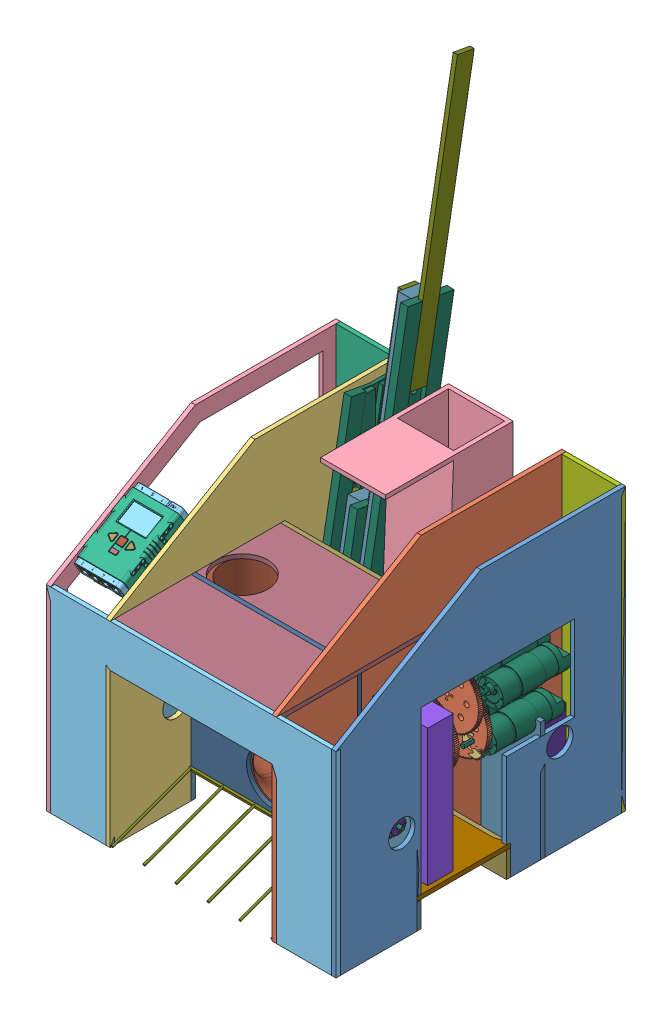
SolidWorks assembly 4290, configuration Default. Lengths in mm.
Overall size (457.2 989.75 483.92).
153 component instances, 53 part files, 145 mates.
Components (placement in the parent):
- Frame Exterior Left Outer-3: Frame Exterior Left Outer [Default] at (209.55 0 215.9) x (0 0 -1) z (1 0 0) size (431.8 419.1 6.35)
- Frame Exterior Left Inner-1: Frame Exterior Left Inner [Default] at (120.65 0 215.9) x (0 0 -1) z (1 0 0) size (431.8 419.1 6.35)
- Frame Exterior Right Inner-1: Frame Exterior Right Inner [Default] at (-127 0 215.9) x (0 0 -1) z (1 0 0) size (431.8 419.1 6.35)
- Frame Exterior Right Outer-1: Frame Exterior Right Outer [Default] at (-215.9 0 215.9) x (0 0 -1) z (1 0 0) size (431.8 419.1 6.35)
- Frame Exterior Front-1: Frame Exterior Front [Default] at (-215.9 0 209.55) size (431.8 292.1 6.35)
- Frame Exterior Back Right-1: Frame Exterior Back Right [Default] at (-215.9 0 -215.9) size (95.25 419.1 6.35)
- Frame Exterior Back Left-1: Frame Exterior Back Left [Default] at (120.65 0 -215.9) size (95.25 419.1 6.35)
- Blower Mockup-1: Blower Mockup [Default] at (209.55 57.15 34.8025) size (190.5 203.2 38.1)
- Frame Bottom Center-1: Frame Bottom Center [Default] at (-215.9 50.8 95.25) x (1 0 0) z (0 1 0) size (431.8 139.7 6.35)
- Frame Intake Front-1: Frame Intake Front [Default] at (-127 50.8 88.9) size (254 254 6.35)
- Ball Intake Tube-1: Ball Intake Tube [Default] at (-120.65 57.15 12.7) size (165.1 241.3 76.2)
- Frame Interior Intake Back-1: Frame Interior Intake Back [Default] at (-215.9 12.7 -44.45) size (431.8 292.1 6.35)
- Frame Interior Intake Top-1: Frame Interior Intake Top [Default] at (-127 298.45 215.9) x (1 0 0) z (0 1 0) size (254 254 6.35)
- Lift Spacer-1: Lift Spacer [Default] at (-109.5375 296.7142 -164.6027) x (1 0 0) z (0 -0.174694 -0.984623) size (19.05 444.5 38.1)
- Lift Spacer-2: Lift Spacer [Default] at (-79.375 550.9074 -209.7022) x (1 0 0) z (0 -0.174694 -0.984623) size (19.05 444.5 38.1)
- Lift Slide A-1: Lift Slide A [Default] at (-115.9125 211.5413 -131.54) x (0 0.984623 -0.174694) z (0 -0.174694 -0.984623) size (406.4 11.11 69.85)
- Lift Slide B-1: Lift Slide B [Default] at (-112.8375 92.0024 -109.4425) x (0 0.984623 -0.174694) z (0 -0.174694 -0.984623) size (406.4 6.35 25.4)
- Lift Slide A-2: Lift Slide A [Default] at (-85.75 91.8495 -110.3041) x (0 0.984623 -0.174694) z (0 -0.174694 -0.984623) size (406.4 11.11 69.85)
- Lift Slide A-3: Lift Slide A [Default] at (-55.5875 346.0428 -155.4036) x (0 0.984623 -0.174694) z (0 -0.174694 -0.984623) size (406.4 11.11 69.85)
- Lift Slide B-2: Lift Slide B [Default] at (-82.675 346.1957 -154.5421) x (0 0.984623 -0.174694) z (0 -0.174694 -0.984623) size (406.4 6.35 25.4)
- Lift Slide B-3: Lift Slide B [Default] at (-52.5125 638.5427 -206.411) x (0 0.984623 -0.174694) z (0 -0.174694 -0.984623) size (406.4 6.35 25.4)
- Mecanum Plate-1: Mecanum Plate [Default] at (203.2 12.7 215.9) x (0 0 -1) z (1 0 0) size (127 101.6 6.35)
- Mecanum Plate-2: Mecanum Plate [Default] at (127 12.7 215.9) x (0 0 -1) z (1 0 0) size (127 101.6 6.35)
- Mecanum Left Assembly-1: Mecanum Left Assembly [Default] at (94.5475 85.9717 60.9515) x (0 -1 0) z (0 0 1) size (116.24 92.45 118.47)
  - Mecanum Left-1: Mecanum Left [Default] at (35.1717 68.1525 91.4485) size (116.24 62.26 118.47)
    - Roller-1: Roller [Default] at (-8.8714 -0.1061 -39.3041) x (-0.709843 -0.615883 -0.341777) z (0.144671 0.347402 -0.926489) size (22.31 28.6 22.31)
    - Washer-1: Washer [Default] at (-2.1949 -6.9473 -40.8283) x (-0.689398 -0.707107 0.15726) z (0.68937 -0.707107 -0.15738) size (6 6 6.25)
    - Bracket Left-1: Bracket Left [Default] at origin size (28.34 25.51 28.03)
    - Roller Hub-2: Roller Hub [Default] at (25.0439 -0.1061 31.5645) x (0.446415 -0.698084 -0.559815) z (0.703674 -0.112601 0.701544) size (15.2 28.65 15.2)
    - Pin-1: Pin [Default] at (40.2927 0.0354 -0.0424) x (0.491193 -0.615883 -0.615969) z (0.871051 0.347402 0.34725) size (2.6 61.8 2.6)
    - Roller-3: Roller [Default] at (-36.2516 0.1061 17.5878) x (-0.306866 0.707107 -0.637051) z (-0.900888 0.000087 0.434052) size (22.31 28.6 22.31)
    - Washer-2: Washer [Default] at (19.6895 6.9473 -35.8342) x (-0.552772 -0.707107 -0.440957) z (0.552849 -0.707107 0.44086) size (6 6 6.25)
    - Roller-5: Roller [Default] at (25.1987 -0.1061 -31.441) x (-0.175349 -0.615883 -0.768076) z (0.814571 0.347402 -0.464528) size (22.31 28.6 22.31)
    - Washer-5: Washer [Default] at (-33.2899 -6.9473 -23.7392) x (-0.306866 -0.707107 0.637051) z (0.306754 -0.707107 -0.637104) size (6 6 6.25)
    - Bracket Left-2: Bracket Left [Default] x (0.62347 0 -0.781847) z (0.781847 0 0.62347) size (28.34 25.51 28.03)
    - Pin-2: Pin [Default] at (25.1544 0.0354 31.4763) x (0.787838 -0.615883 0) z (0.271578 0.347402 0.897528) size (2.6 61.8 2.6)
    - Roller-6: Roller [Default] at (-36.3528 0.1061 -17.3777) x (0.306754 0.707107 -0.637104) z (-0.901039 0.000087 -0.433738) size (22.31 28.6 22.31)
    - Washer-6: Washer [Default] at (-15.741 6.9473 -37.7357) x (-0.689398 -0.707107 0.15726) z (0.68937 -0.707107 -0.15738) size (6 6 6.25)
    - Roller-9: Roller [Default] at (40.2927 -0.1061 0.099) x (0.491193 -0.615883 -0.615969) z (0.871051 0.347402 0.34725) size (22.31 28.6 22.31)
    - Washer-8: Washer [Default] at (-39.3157 -6.9473 11.2269) x (0.306754 -0.707107 0.637104) z (-0.306866 -0.707107 -0.637051) size (6 6 6.25)
    - Bracket Left-3: Bracket Left [Default] x (-0.22257 0 -0.974917) z (0.974917 0 -0.22257) size (28.34 25.51 28.03)
    - Bracket Left-4: Bracket Left [Default] x (-0.901001 0 -0.433816) z (0.433816 0 -0.901001) size (28.34 25.51 28.03)
    - Roller Hub-6: Roller Hub [Default] at (-36.2516 0.1061 17.5878) x (-0.446512 0.698084 -0.559737) z (-0.840471 -0.112601 0.530028) size (15.2 28.65 15.2)
    - Roller-10: Roller [Default] at (-9.0782 0.1061 -39.2568) x (0.68937 0.707107 -0.15738) z (-0.222655 0.000087 -0.974897) size (22.31 28.6 22.31)
    - Washer-10: Washer [Default] at (-39.3176 6.9473 -11.2201) x (-0.306866 -0.707107 0.637051) z (0.306754 -0.707107 -0.637104) size (6 6 6.25)
    - Roller-13: Roller [Default] at (25.0439 -0.1061 31.5645) x (0.787838 -0.615883 0) z (0.271578 0.347402 0.897528) size (22.31 28.6 22.31)
    - Washer-11: Washer [Default] at (-15.7344 -6.9473 37.7385) x (0.68937 -0.707107 0.15738) z (-0.689398 -0.707107 -0.15726) size (6 6 6.25)
    - Bracket Left-5: Bracket Left [Default] x (-0.900926 0 0.433974) z (-0.433974 0 -0.900926) size (28.34 25.51 28.03)
    - Roller Hub-8: Roller Hub [Default] at (-36.3437 -0.1061 17.3967) x (0.446512 -0.698084 0.559737) z (-0.840471 -0.112601 0.530028) size (15.2 28.65 15.2)
    - Roller-14: Roller [Default] at (25.0329 0.1061 -31.5732) x (0.552849 0.707107 0.44086) z (0.623402 0.000087 -0.781901) size (22.31 28.6 22.31)
    - Washer-14: Washer [Default] at (-33.2858 6.9473 23.745) x (0.306754 -0.707107 0.637104) z (-0.306866 -0.707107 -0.637051) size (6 6 6.25)
    - Roller Hub-11: Roller Hub [Default] at (25.1987 -0.1061 -31.441) x (-0.645131 -0.698084 -0.310619) z (0.527331 -0.112601 -0.842166) size (15.2 28.65 15.2)
    - Roller Hub-12: Roller Hub [Default] at (25.0329 0.1061 -31.5732) x (0.645131 0.698084 0.310619) z (0.527331 -0.112601 -0.842166) size (15.2 28.65 15.2)
    - Pin-5: Pin [Default] at (-8.9197 0.0354 39.293) x (0.491301 -0.615883 0.615883) z (-0.532275 0.347402 0.772007) size (2.6 61.8 2.6)
    - Washer-15: Washer [Default] at (19.6958 -6.9473 35.8307) x (0.552849 -0.707107 -0.44086) z (-0.552772 -0.707107 0.440957) size (6 6 6.25)
    - Bracket Left-6: Bracket Left [Default] x (-0.222399 0 0.974956) z (-0.974956 0 -0.222399) size (28.34 25.51 28.03)
    - Roller Hub-13: Roller Hub [Default] at (40.2927 -0.1061 0.099) x (-0.159363 -0.698084 -0.698056) z (0.98722 -0.112601 -0.112773) size (15.2 28.65 15.2)
    - Roller Hub-14: Roller Hub [Default] at (-36.3528 0.1061 -17.3777) x (0.159242 0.698084 -0.698084) z (-0.938409 -0.112601 -0.326663) size (15.2 28.65 15.2)
    - Roller-17: Roller [Default] at (40.2927 0.1061 -0.1131) x (0 0.707107 0.707107) z (1 0.000087 -0.000087) size (22.31 28.6 22.31)
    - Washer-17: Washer [Default] at (-2.1877 6.9473 40.8287) x (0.68937 -0.707107 0.15738) z (-0.689398 -0.707107 -0.15726) size (6 6 6.25)
    - Roller Hub-17: Roller Hub [Default] at (40.2927 0.1061 -0.1131) x (0.159363 0.698084 0.698056) z (0.98722 -0.112601 -0.112773) size (15.2 28.65 15.2)
    - Pin-7: Pin [Default] at (-36.2823 0.0354 17.5241) x (-0.175215 -0.615883 0.768107) z (-0.935449 0.347402 0.065166) size (2.6 61.8 2.6)
    - Washer-19: Washer [Default] at (40.2939 -6.9473 6.9403) x (0 -0.707107 -0.707107) z (0.000123 -0.707107 0.707107) size (6 6 6.25)
    - Bracket Left-7: Bracket Left [Default] x (0.623607 0 0.781738) z (-0.781738 0 0.623607) size (28.34 25.51 28.03)
    - Roller Hub-18: Roller Hub [Default] at (-36.2608 -0.1061 -17.5689) x (-0.159242 -0.698084 0.698084) z (-0.938409 -0.112601 -0.326663) size (15.2 28.65 15.2)
    - Roller-20: Roller [Default] at (-9.0576 -0.1061 39.2616) x (0.491301 -0.615883 0.615883) z (-0.532275 0.347402 0.772007) size (22.31 28.6 22.31)
    - Washer-20: Washer [Default] at (30.5578 6.9473 27.1659) x (0.552849 -0.707107 -0.44086) z (-0.552772 -0.707107 0.440957) size (6 6 6.25)
    - Pin-9: Pin [Default] at (-36.3221 0.0354 -17.4414) x (-0.709783 -0.615883 0.341901) z (-0.634175 0.347402 -0.690749) size (2.6 61.8 2.6)
    - Hub Inner Left-1: Hub Inner Left [Default] at origin size (62.26 19.81 61.13)
    - Roller Hub-21: Roller Hub [Default] at (-9.0645 -0.1061 39.26) x (0.716016 -0.698084 0) z (-0.109781 -0.112601 0.987557) size (15.2 28.65 15.2)
    - Roller Hub-22: Roller Hub [Default] at (-8.8577 0.1061 39.3072) x (-0.716016 0.698084 0) z (-0.109781 -0.112601 0.987557) size (15.2 28.65 15.2)
    - Roller Hub-23: Roller Hub [Default] at (-9.0782 0.1061 -39.2568) x (0.645077 0.698084 -0.310732) z (-0.329669 -0.112601 -0.937358) size (15.2 28.65 15.2)
    - Roller-22: Roller [Default] at (-36.3437 -0.1061 17.3967) x (-0.175215 -0.615883 0.768107) z (-0.935449 0.347402 0.065166) size (22.31 28.6 22.31)
    - Washer-23: Washer [Default] at (40.2915 6.9473 -6.9544) x (0 -0.707107 -0.707107) z (0.000123 -0.707107 0.707107) size (6 6 6.25)
    - Roller Hub-24: Roller Hub [Default] at (25.2097 0.1061 31.4322) x (-0.446415 0.698084 0.559815) z (0.703674 -0.112601 0.701544) size (15.2 28.65 15.2)
    - Pin-11: Pin [Default] at (-9.0092 0.0354 -39.2726) x (-0.709843 -0.615883 -0.341777) z (0.144671 0.347402 -0.926489) size (2.6 61.8 2.6)
    - Roller-24: Roller [Default] at (25.2152 0.1061 31.4278) x (-0.552772 0.707107 0.440957) z (0.623675 0.000087 0.781684) size (22.31 28.6 22.31)
    - Roller Hub-27: Roller Hub [Default] at (-8.8714 -0.1061 -39.3041) x (-0.645077 -0.698084 0.310732) z (-0.329669 -0.112601 -0.937358) size (15.2 28.65 15.2)
    - Roller-25: Roller [Default] at (-36.2608 -0.1061 -17.5689) x (-0.709783 -0.615883 0.341901) z (-0.634175 0.347402 -0.690749) size (22.31 28.6 22.31)
    - Washer-26: Washer [Default] at (30.553 -6.9473 -27.1713) x (-0.552772 -0.707107 -0.440957) z (0.552849 -0.707107 0.44086) size (6 6 6.25)
    - Hub Outer Left-1: Hub Outer Left [Default] at origin size (61.9 23.71 60.76)
    - Pin-13: Pin [Default] at (25.0881 0.0354 -31.5291) x (-0.175349 -0.615883 -0.768076) z (0.814571 0.347402 -0.464528) size (2.6 61.8 2.6)
    - Roller-28: Roller [Default] at (-8.8508 0.1061 39.3087) x (-0.689398 0.707107 -0.15726) z (-0.222314 0.000087 0.974975) size (22.31 28.6 22.31)
  - Mecanum Hub A-1: Mecanum Hub A [Default] at (35.1717 56.1525 91.4485) x (1 0 0) z (0 -1 0) size (50 50 12)
  - Mecanum Hub B-1: Mecanum Hub B [Default] at (35.1717 80.1525 91.4485) x (1 0 0) z (0 -1 0) size (50 50 12)
  - Tetrix Axle Hub-1: Tetrix Axle Hub [Default] at (35.1717 89.1525 91.4485) x (1 0 0) z (0 -1 0) size (22.1 22.1 9.5)
    - Tetrix Axle Hub Body-1: Tetrix Axle Hub Body [Default] at origin size (22.1 22.1 9.5)
    - Tetrix Axle Hub Set Screw-1: Tetrix Axle Hub Set Screw [Default] at (6.9308 6.9308 -3.325) x (-0.707107 0.707107 0) z (0 0 1) size (4.83 7.94 4.83)
  - Tetrix Axle Hub-2: Tetrix Axle Hub [Default] at (35.1717 47.1525 91.4485) x (1 0 0) z (0 1 0) size (22.1 22.1 9.5)
    - Tetrix Axle Hub Body-1: Tetrix Axle Hub Body [Default] at origin size (22.1 22.1 9.5)
    - Tetrix Axle Hub Set Screw-1: Tetrix Axle Hub Set Screw [Default] at (6.9308 6.9308 -3.325) x (-0.707107 0.707107 0) z (0 0 1) size (4.83 7.94 4.83)
  - Tetrix Bushing Bronze-1: Tetrix Bushing Bronze [Default] at (35.1717 40.4025 91.4485) x (-0.837169 0 -0.546944) z (-0.546944 0 0.837169) size (9.56 12.71 9.56)
  - Tetrix Bushing Bronze-2: Tetrix Bushing Bronze [Default] at (35.1717 104.3025 91.4485) x (-0.837169 0 -0.546944) z (-0.546944 0 0.837169) size (9.56 12.71 9.56)
  - Tetrix Bushing Bronze-3: Tetrix Bushing Bronze [Default] at (35.1717 107.4275 91.4485) x (0.996434 0 -0.084371) z (0.084371 0 0.996434) size (9.56 12.71 9.56)
  - Tetrix Sprocket 24T-1: Tetrix Sprocket 24T [Default] at (35.1717 99.9025 91.4485) x (1 0 0) z (0 -1 0) size (52 52 6.8)
  - Tetrix Axle Spacer Small-1: Tetrix Axle Spacer Small [Default] at (35.1717 105.865 91.4485) x (1 0 0) z (0 -1 0) size (9.5 9.5 3.12)
- Mecanum Back Plate-1: Mecanum Back Plate [Default] at (120.65 12.7 88.9) size (95.25 177.8 6.35)
- Mecanum Back Plate-2: Mecanum Back Plate [Default] at (-215.9 12.7 88.9) size (95.25 177.8 6.35)
- Mecanum Back Plate-3: Mecanum Back Plate [Default] at (-215.9 12.7 -95.25) size (95.25 177.8 6.35)
- Mecanum Back Plate-4: Mecanum Back Plate [Default] at (120.65 12.7 -95.25) size (95.25 177.8 6.35)
- Mecanum Plate-3: Mecanum Plate [Default] at (-209.55 12.7 215.9) x (0 0 -1) z (1 0 0) size (127 101.6 6.35)
- Mecanum Plate-4: Mecanum Plate [Default] at (-133.35 12.7 215.9) x (0 0 -1) z (1 0 0) size (127 101.6 6.35)
- Mecanum Plate-5: Mecanum Plate [Default] at (-209.55 12.7 -88.9) x (0 0 -1) z (1 0 0) size (127 101.6 6.35)
- Mecanum Plate-6: Mecanum Plate [Default] at (-133.35 12.7 -88.9) x (0 0 -1) z (1 0 0) size (127 101.6 6.35)
- Mecanum Plate-7: Mecanum Plate [Default] at (127 12.7 -88.9) x (0 0 -1) z (1 0 0) size (127 101.6 6.35)
- Mecanum Plate-8: Mecanum Plate [Default] at (203.2 12.7 -88.9) x (0 0 -1) z (1 0 0) size (127 101.6 6.35)
- Tetrix Motor NeveRest (AM-2964)-1: Tetrix Motor NeveRest (AM-2964) [Default] at (151.8 150.3 117.75) x (0 -0.999926 0.012192) z (1 0 0) size (38 38 133.81)
- Tetrix Sprocket 16T-1: Tetrix Sprocket 16T [Default] at (194.45 150.2147 110.7505) x (0 0 1) z (-1 0 0) size (36 36 6.8)
- Tetrix Motor Hub-1: Tetrix Motor Hub [Default] at (197.25 150.2147 110.7505) x (0 0 1) z (-1 0 0) size (22 22 9.5)
  - Tetrix Motor Hub Body-1: Tetrix Motor Hub Body [Default] at origin size (22 22 9.5)
  - Tetrix Motor Hub Set Screw-1: Tetrix Motor Hub Set Screw [Default] at (8.5735 5.5677 -3.325) x (-0.544639 0.838671 0) z (0 0 1) size (4.83 7.94 4.83)
- Tetrix Motor Mount-2: Tetrix Motor Mount [Default] at (171.45 150.3 117.75) x (0 -1 0) z (-1 0 0) size (72 45 12.7)
- Tetrix Gear 120T-1: Tetrix Gear 120T [Default] at (128.024 177.2721 -1.1574) x (0 0 -1) z (1 0 0) size (6.2 97.58 97.58)
- Tetrix Gear 40T-1: Tetrix Gear 40T [Default] at (128.024 177.2721 -13.5574) x (0 0 1) z (0 -1 0) size (6.2 33.53 33.53)
- Tetrix Gear 120T-2: Tetrix Gear 120T [Default] at (157.3037 239.8524 -7.3574) x (0 0 -1) z (1 0 0) size (6.2 97.58 97.58)
- Tetrix Gear 120T-3: Tetrix Gear 120T [Default] at (164.7517 209.4475 -13.5574) x (0 0 -1) z (1 0 0) size (6.2 97.58 97.58)
- Tetrix Gear 40T-2: Tetrix Gear 40T [Default] at (157.3037 239.8524 -19.7574) x (0 0 1) z (0 -1 0) size (6.2 33.53 33.53)
- Tetrix Gear 40T-3: Tetrix Gear 40T [Default] at (146.5434 116.0004 -7.3574) x (0 0 1) z (-1 0 0) size (6.2 33.53 33.53)
- Tetrix Gear 40T-4: Tetrix Gear 40T [Default] at (164.7517 209.4475 -25.9574) x (0 0 1) z (0 -1 0) size (6.2 33.53 33.53)
- Tetrix Gear 40T-5: Tetrix Gear 40T [Default] at (144.3577 235.6001 -13.5574) x (0 0 -1) z (1 0 0) size (6.2 33.53 33.53)
- Tetrix Gear 40T-6: Tetrix Gear 40T [Default] at (189.3184 184.8698 -13.5574) x (0 0 -1) z (1 0 0) size (6.2 33.53 33.53)
- Tetrix Gear 40T-7: Tetrix Gear 40T [Default] at (186.2973 234.0527 -13.5574) x (0 0 -1) z (1 0 0) size (6.2 33.53 33.53)
- Tetrix Motor NeveRest (AM-2964)-2: Tetrix Motor NeveRest (AM-2964) [Default] at (143.3435 235.8716 -82.6306) size (38 38 133.81)
- Tetrix Motor NeveRest (AM-2964)-3: Tetrix Motor NeveRest (AM-2964) [Default] at (190.0348 184.6453 -57.044) size (38 38 133.81)
- Tetrix Motor NeveRest (AM-2964)-4: Tetrix Motor NeveRest (AM-2964) [Default] at (186.8147 235.871 -69.9455) size (38 38 133.81)
- Tetrix Motor NeveRest (AM-2964)-5: Tetrix Motor NeveRest (AM-2964) [Default] at (143.8802 183.8806 -63.3083) size (38 38 133.81)
- Output Mockup-1: Output Mockup [Default] at (-48.26 127 -114.3) size (96.52 304.8 190.5)
- NXT-1: NXT [Default] at (-173.7875 331.0497 125.1235) x (1 0 0) z (0 -0.50702 0.861934) size (71.61 47.78 111.26)
  - NXT Interior-1: NXT Interior [Default] at origin size (68.88 22 111.26)
  - NXT Shell-1: NXT Shell [Default] at (0.0375 -0.17 0) size (71.61 23.57 95.25)
  - NXT Battery Case-1: NXT Battery Case [Default] x (1 0 0) z (0 0 -1) size (71.38 16.13 104.22)
  - NXT Battery-1: NXT Battery [Default] at (0 -14.125 0) x (-1 0 0) z (0 0 1) size (69.68 23.25 89.34)
  - NXT Socket-1: NXT Socket [Default] at (-23.1925 13 55.625) x (1 0 0) z (0 0 -1) size (12.5 15 12.59)
  - NXT Socket-2: NXT Socket [Default] at (-7.7325 13 55.625) x (1 0 0) z (0 0 -1) size (12.5 15 12.59)
  - NXT Socket-3: NXT Socket [Default] at (7.7275 13 55.625) x (1 0 0) z (0 0 -1) size (12.5 15 12.59)
  - NXT Socket-4: NXT Socket [Default] at (23.1875 13 55.625) x (1 0 0) z (0 0 -1) size (12.5 15 12.59)
  - NXT Socket-5: NXT Socket [Default] at (-23.1925 13 -55.625) x (-1 0 0) z (0 0 1) size (12.5 15 12.59)
  - NXT Socket-6: NXT Socket [Default] at (-7.7325 13 -55.625) x (-1 0 0) z (0 0 1) size (12.5 15 12.59)
  - NXT Socket-7: NXT Socket [Default] at (7.7275 13 -55.625) x (-1 0 0) z (0 0 1) size (12.5 15 12.59)
  - NXT Socket USB-1: NXT Socket USB [Default] at (23.1875 10.75 -43.125) x (-1 0 0) z (0 0 -1) size (12.5 10.5 12.5)
  - NXT Button 1-1: NXT Button 1 [Default] at (0.0375 22 10) size (10.5 1.65 10.5)
  - NXT Button 2-1: NXT Button 2 [Default] at (-14.4625 22 10) size (9.5 1.65 10.5)
  - NXT Button 2-2: NXT Button 2 [Default] at (14.5375 22 10) x (-1 0 0) z (0 0 -1) size (9.5 1.65 10.5)
  - NXT Button 3-1: NXT Button 3 [Default] at (0.0375 22 23.375) size (10.5 1.65 5.75)
- HiTechnic Motor Controller-1: HiTechnic Motor Controller [Default] at (-137.476 259.716 -113.5834) x (0 1 0) z (0 0 1) size (89 25.26 72)
- HiTechnic Motor Controller-2: HiTechnic Motor Controller [Default] at (-162.476 257.4228 -166.1997) x (0 1 0) z (0 0 1) size (89 25.26 72)
- HiTechnic Motor Controller-3: HiTechnic Motor Controller [Default] at (-137.476 353.393 -108.7977) x (0 1 0) z (0 0 1) size (89 25.26 72)
- HiTechnic Motor Controller-4: HiTechnic Motor Controller [Default] at (-162.476 351.111 -163.6324) x (0 1 0) z (0 0 1) size (89 25.26 72)
- Lift Slide A-5: Lift Slide A [Default] at (-115.9125 207.9 -182.35) x (0 1 0) z (0 0 -1) size (406.4 11.11 69.85)
- Lift Slide A-6: Lift Slide A [Default] at (115.9125 207.9 -179.6) x (0 1 0) z (0 0 1) size (406.4 11.11 69.85)
- Goal Lift Mockup-1: Goal Lift Mockup [Default] at (-4.3125 128.6076 -194.55) size (219.08 304.8 44.45)
- Rake-1: Rake [Default] at (0 57.15 96.8375) x (1 0 0) z (0 -0.342538 0.939504) size (241.3 3.17 127)
- Tetrix Battery-1: Tetrix Battery [Default] at (-159.1957 57.15 -63.9411) x (0 0 1) z (-1 0 0) size (132 44 44)
Mates (geometry in assembly coordinates):
- Distance11: distance = 82.55 mm anti-aligned: plane of Frame Exterior Right Inner-1 through (-127 0 215.9) normal (-1 0 0); plane of Frame Exterior Right Outer-1 through (-209.55 0 215.9) normal (1 0 0)
- Coincident8: coincident aligned: plane of Frame Exterior Right Inner-1 through (-120.65 431.8 0) normal (0 1 0); plane of Frame Exterior Right Outer-1 through (-209.55 431.8 0) normal (0 1 0)
- Coincident10: coincident aligned: plane of Frame Exterior Right Inner-1 through (-120.65 12.7 88.9) normal (0 0 -1); plane of Frame Exterior Right Outer-1 through (-209.55 12.7 88.9) normal (0 0 -1)
- Coincident11: coincident aligned: plane of Frame Exterior Left Inner-1 through (127 12.7 88.9) normal (0 0 -1); plane of Frame Exterior Right Inner-1 through (-120.65 12.7 88.9) normal (0 0 -1)
- Coincident18: coincident aligned: plane of Frame Exterior Right Inner-1 through (-120.65 12.7 -215.9) normal (0 0 -1); plane of Frame Exterior Back Right-1 through (-215.9 0 -215.9) normal (0 0 -1)
- Coincident19: coincident aligned: plane of Frame Exterior Right Inner-1 through (-120.65 431.8 0) normal (0 1 0); plane of Frame Exterior Back Right-1 through (-215.9 431.8 -209.55) normal (0 1 0)
- Coincident20: coincident aligned: plane of Frame Exterior Right Inner-1 through (-120.65 0 215.9) normal (1 0 0); plane of Frame Exterior Back Right-1 through (-120.65 431.8 -209.55) normal (1 0 0)
- Coincident23: coincident aligned: plane of Frame Exterior Left Inner-1 through (127 50.8 -38.1) normal (0 -1 0); plane of Frame Bottom Center-1 through (-215.9 50.8 95.25) normal (0 -1 0)
- Coincident26: coincident anti-aligned: plane of Blower Mockup-1 through (19.05 57.15 72.9025) normal (0 -1 0); plane of Frame Bottom Center-1 through (-215.9 57.15 95.25) normal (0 1 0)
- Coincident27: coincident aligned: plane of Frame Bottom Center-1 through (-215.9 57.15 95.25) normal (0 0 1); plane of Frame Intake Front-1 through (-127 50.8 95.25) normal (0 0 1)
- Coincident28: coincident aligned: plane of Frame Bottom Center-1 through (-215.9 50.8 95.25) normal (0 -1 0); plane of Frame Intake Front-1 through (-127 50.8 95.25) normal (0 -1 0)
- Coincident30: coincident aligned: plane of Frame Exterior Left Inner-1 through (127 0 215.9) normal (1 0 0); plane of Frame Intake Front-1 through (127 50.8 95.25) normal (1 0 0)
- Coincident31: coincident anti-aligned: plane of Frame Intake Front-1 through (-127 50.8 88.9) normal (0 0 -1); plane of Ball Intake Tube-1 through (-120.65 57.15 88.9) normal (0 0 1)
- Coincident32: coincident anti-aligned: plane of Frame Bottom Center-1 through (-215.9 57.15 95.25) normal (0 1 0); plane of Ball Intake Tube-1 through (-120.65 57.15 88.9) normal (0 -1 0)
- Coincident33: coincident anti-aligned: plane of Frame Exterior Right Inner-1 through (-120.65 0 215.9) normal (1 0 0); plane of Ball Intake Tube-1 through (-120.65 298.45 88.9) normal (-1 0 0)
- Coincident34: coincident aligned: plane of Frame Exterior Left Inner-1 through (127 12.7 -38.1) normal (0 -1 0); plane of Frame Interior Intake Back-1 through (-215.9 12.7 -38.1) normal (0 -1 0)
- Coincident37: coincident aligned: plane of Frame Exterior Front-1 through (-215.9 304.8 215.9) normal (0 1 0); plane of Frame Interior Intake Top-1 through (-127 304.8 215.9) normal (0 1 0)
- Coincident38: coincident aligned: plane of Frame Exterior Front-1 through (-215.9 0 215.9) normal (0 0 1); plane of Frame Interior Intake Top-1 through (-127 304.8 215.9) normal (0 0 1)
- Coincident40: coincident aligned: plane of Frame Exterior Left Inner-1 through (127 0 215.9) normal (1 0 0); plane of Frame Interior Intake Top-1 through (127 304.8 215.9) normal (1 0 0)
- Coincident41: coincident anti-aligned: plane of Frame Exterior Right Inner-1 through (-120.65 0 215.9) normal (1 0 0); plane of Lift Slide A-1 through (-120.65 413.6326 -201.4695) normal (-1 0 0)
- Coincident42: coincident anti-aligned: plane of Lift Slide A-1 through (-115.8875 421.9524 -154.5769) normal (1 0 0); plane of Lift Slide B-1 through (-115.8875 297.8235 -158.3503) normal (-1 0 0)
- Coincident43: coincident anti-aligned: plane of Lift Slide A-1 through (-115.8875 417.5152 -179.5863) normal (0 0.174694 0.984623); plane of Lift Slide B-1 through (-115.8875 297.8235 -158.3503) normal (0 -0.174694 -0.984623)
- Coincident44: coincident anti-aligned: plane of Lift Spacer-1 through (-109.5375 296.7142 -164.6027) normal (-1 0 0); plane of Lift Slide B-1 through (-109.5375 297.8235 -158.3503) normal (1 0 0)
- Coincident45: coincident anti-aligned: plane of Lift Spacer-1 through (-90.4875 296.7142 -164.6027) normal (1 0 0); plane of Lift Slide A-2 through (-90.4875 293.9409 -180.2335) normal (-1 0 0)
- Coincident46: coincident anti-aligned: plane of Lift Slide A-2 through (-85.725 302.2607 -133.3409) normal (1 0 0); plane of Lift Slide B-2 through (-85.725 552.0167 -203.4499) normal (-1 0 0)
- Coincident47: coincident anti-aligned: plane of Lift Spacer-2 through (-79.375 550.9074 -209.7022) normal (-1 0 0); plane of Lift Slide B-2 through (-79.375 552.0167 -203.4499) normal (1 0 0)
- Coincident48: coincident anti-aligned: plane of Lift Spacer-2 through (-60.325 550.9074 -209.7022) normal (1 0 0); plane of Lift Slide A-3 through (-60.325 548.1341 -225.3331) normal (-1 0 0)
- Coincident49: coincident anti-aligned: plane of Lift Slide A-3 through (-55.5625 556.4539 -178.4405) normal (1 0 0); plane of Lift Slide B-3 through (-55.5625 844.3637 -255.3188) normal (-1 0 0)
- Distance13: distance = 15.875 mm aligned: plane of Lift Slide A-1 through (-109.5375 413.6326 -201.4695) normal (0 -0.174694 -0.984623); plane of Lift Spacer-1 through (-90.4875 296.7142 -164.6027) normal (0 -0.174694 -0.984623)
- Distance14: distance = 15.875 mm aligned: plane of Lift Slide A-2 through (-79.375 293.9409 -180.2335) normal (0 -0.174694 -0.984623); plane of Lift Spacer-1 through (-90.4875 296.7142 -164.6027) normal (0 -0.174694 -0.984623)
- Coincident52: coincident aligned: plane of Lift Spacer-1 through (-90.4875 296.7142 -164.6027) normal (0 -0.174694 -0.984623); plane of Lift Spacer-2 through (-60.325 550.9074 -209.7022) normal (0 -0.174694 -0.984623)
- Coincident53: coincident aligned: plane of Lift Slide A-2 through (-79.375 293.9409 -180.2335) normal (0 -0.174694 -0.984623); plane of Lift Slide A-3 through (-49.2125 548.1341 -225.3331) normal (0 -0.174694 -0.984623)
- Coincident54: coincident aligned: plane of Lift Slide B-2 through (-85.725 552.0167 -203.4499) normal (0 -0.174694 -0.984623); plane of Lift Slide B-3 through (-55.5625 844.3637 -255.3188) normal (0 -0.174694 -0.984623)
- Coincident55: coincident aligned: plane of Lift Slide B-1 through (-115.8875 297.8235 -158.3503) normal (0 -0.174694 -0.984623); plane of Lift Slide B-2 through (-85.725 552.0167 -203.4499) normal (0 -0.174694 -0.984623)
- Coincident56: coincident aligned: plane of Lift Spacer-1 through (-90.4875 296.7142 -164.6027) normal (0 0.984623 -0.174694); plane of Lift Slide B-1 through (-115.8875 297.8235 -158.3503) normal (0 0.984623 -0.174694)
- Coincident57: coincident aligned: plane of Lift Spacer-1 through (-90.4875 296.7142 -164.6027) normal (0 0.984623 -0.174694); plane of Lift Slide A-2 through (-90.4875 293.9409 -180.2335) normal (0 0.984623 -0.174694)
- Coincident58: coincident aligned: plane of Lift Spacer-2 through (-60.325 550.9074 -209.7022) normal (0 0.984623 -0.174694); plane of Lift Slide B-2 through (-85.725 552.0167 -203.4499) normal (0 0.984623 -0.174694)
- Coincident59: coincident aligned: plane of Lift Spacer-2 through (-60.325 550.9074 -209.7022) normal (0 0.984623 -0.174694); plane of Lift Slide A-3 through (-60.325 548.1341 -225.3331) normal (0 0.984623 -0.174694)
- Coincident63: coincident aligned: plane of Frame Exterior Front-1 through (-215.9 0 215.9) normal (0 0 1); plane of Mecanum Plate-1 through (209.55 12.7 215.9) normal (0 0 1)
- Coincident64: coincident anti-aligned: plane of Frame Exterior Left Inner-1 through (127 0 215.9) normal (1 0 0); plane of Mecanum Plate-2 through (127 12.7 215.9) normal (-1 0 0)
- Coincident65: coincident aligned: plane of Frame Exterior Front-1 through (-215.9 0 215.9) normal (0 0 1); plane of Mecanum Plate-2 through (133.35 12.7 215.9) normal (0 0 1)
- Coincident66: coincident aligned: plane of Mecanum Plate-1 through (209.55 12.7 215.9) normal (0 -1 0); plane of Mecanum Plate-2 through (133.35 12.7 215.9) normal (0 -1 0)
- Concentric1: concentric anti-aligned: cylinder of Mecanum Plate-2 through (133.35 50.8 152.4) axis (-1 0 0) radius 4; cylinder of Mecanum Left Assembly-1/Tetrix Bushing Bronze-1 through (134.95 50.8 152.4) axis (1 0 0) radius 4
- Coincident67: coincident anti-aligned: plane of Mecanum Plate-2 through (133.35 12.7 215.9) normal (1 0 0); plane of Mecanum Left Assembly-1/Tetrix Bushing Bronze-1 through (133.35 47.4513 154.5878) normal (-1 0 0)
- Distance16: distance = 215.9 mm aligned: plane of Frame Exterior Left Outer-3 through (215.9 0 215.9) normal (1 0 0); plane of assembly through (0 0 0) normal (1 0 0)
- Distance17: distance = 50.8 mm anti-aligned: plane of Frame Exterior Left Outer-3 through (215.9 50.8 -38.1) normal (0 -1 0); plane of assembly through (0 0 0) normal (0 1 0)
- Distance18: distance = 215.9 mm aligned: plane of Frame Exterior Left Outer-3 through (215.9 304.8 215.9) normal (0 0 1); plane of assembly through (0 0 0) normal (0 0 1)
- Coincident74: coincident aligned: plane of Frame Exterior Left Inner-1 through (127 304.8 215.9) normal (0 0 1); plane of Frame Exterior Left Outer-3 through (215.9 304.8 215.9) normal (0 0 1)
- Coincident75: coincident aligned: plane of Frame Exterior Front-1 through (-215.9 0 215.9) normal (0 0 1); plane of Frame Exterior Left Outer-3 through (215.9 304.8 215.9) normal (0 0 1)
- Coincident76: coincident anti-aligned: plane of Mecanum Plate-1 through (209.55 12.7 215.9) normal (1 0 0); plane of Frame Exterior Left Outer-3 through (209.55 0 215.9) normal (-1 0 0)
- Coincident77: coincident aligned: plane of Mecanum Plate-1 through (209.55 12.7 215.9) normal (0 -1 0); plane of Frame Exterior Left Outer-3 through (215.9 12.7 215.9) normal (0 -1 0)
- Coincident78: coincident aligned: plane of Frame Exterior Front-1 through (215.9 12.7 215.9) normal (0 -1 0); plane of Mecanum Plate-1 through (209.55 12.7 215.9) normal (0 -1 0)
- Coincident79: coincident aligned: plane of Frame Exterior Front-1 through (215.9 304.8 215.9) normal (1 0 0); plane of Frame Exterior Left Outer-3 through (215.9 0 215.9) normal (1 0 0)
- Coincident80: coincident aligned: plane of Frame Exterior Left Outer-3 through (215.9 12.7 -38.1) normal (0 -1 0); plane of Frame Exterior Left Inner-1 through (127 12.7 -38.1) normal (0 -1 0)
- Distance19: distance = 82.55 mm anti-aligned: plane of Frame Exterior Left Inner-1 through (127 0 215.9) normal (1 0 0); plane of Frame Exterior Left Outer-3 through (209.55 0 215.9) normal (-1 0 0)
- Coincident82: coincident aligned: plane of Frame Exterior Left Outer-3 through (215.9 12.7 -38.1) normal (0 -1 0); plane of Frame Exterior Right Outer-1 through (-209.55 12.7 -38.1) normal (0 -1 0)
- Distance20: distance = 431.8 mm anti-aligned: plane of Frame Exterior Left Outer-3 through (215.9 0 215.9) normal (1 0 0); plane of Frame Exterior Right Outer-1 through (-215.9 0 215.9) normal (-1 0 0)
- Coincident84: coincident aligned: plane of Frame Exterior Left Outer-3 through (215.9 12.7 -38.1) normal (0 -1 0); plane of Frame Exterior Back Left-1 through (120.65 12.7 -209.55) normal (0 -1 0)
- Coincident85: coincident aligned: plane of Frame Exterior Left Outer-3 through (215.9 0 215.9) normal (1 0 0); plane of Frame Exterior Back Left-1 through (215.9 431.8 -209.55) normal (1 0 0)
- Coincident87: coincident aligned: plane of Frame Exterior Left Outer-3 through (215.9 0 215.9) normal (1 0 0); plane of Frame Bottom Center-1 through (215.9 57.15 95.25) normal (1 0 0)
- Coincident88: coincident aligned: plane of Frame Bottom Center-1 through (-215.9 57.15 -44.45) normal (0 0 -1); plane of Frame Interior Intake Back-1 through (-215.9 12.7 -44.45) normal (0 0 -1)
- Coincident89: coincident aligned: plane of Frame Exterior Left Inner-1 through (127 50.8 -38.1) normal (0 0 1); plane of Frame Interior Intake Back-1 through (-215.9 12.7 -38.1) normal (0 0 1)
- Coincident90: coincident aligned: plane of Frame Exterior Left Outer-3 through (215.9 0 215.9) normal (1 0 0); plane of Frame Interior Intake Back-1 through (215.9 12.7 -38.1) normal (1 0 0)
- Coincident91: coincident aligned: plane of Frame Exterior Left Inner-1 through (127 12.7 88.9) normal (0 0 -1); plane of Mecanum Back Plate-1 through (120.65 12.7 88.9) normal (0 0 -1)
- Coincident92: coincident aligned: plane of Frame Exterior Left Inner-1 through (127 12.7 215.9) normal (0 -1 0); plane of Mecanum Back Plate-1 through (120.65 12.7 95.25) normal (0 -1 0)
- Coincident93: coincident aligned: plane of Frame Exterior Left Inner-1 through (120.65 0 215.9) normal (-1 0 0); plane of Mecanum Back Plate-1 through (120.65 12.7 95.25) normal (-1 0 0)
- Coincident94: coincident aligned: plane of Mecanum Back Plate-1 through (120.65 12.7 88.9) normal (0 0 -1); plane of Mecanum Back Plate-2 through (-215.9 12.7 88.9) normal (0 0 -1)
- Coincident95: coincident aligned: plane of Frame Exterior Right Outer-1 through (-209.55 12.7 215.9) normal (0 -1 0); plane of Mecanum Back Plate-2 through (-215.9 12.7 95.25) normal (0 -1 0)
- Coincident96: coincident aligned: plane of Frame Exterior Right Outer-1 through (-215.9 0 215.9) normal (-1 0 0); plane of Mecanum Back Plate-2 through (-215.9 12.7 95.25) normal (-1 0 0)
- Coincident97: coincident aligned: plane of Frame Exterior Right Outer-1 through (-215.9 0 215.9) normal (-1 0 0); plane of Mecanum Back Plate-3 through (-215.9 12.7 -88.9) normal (-1 0 0)
- Coincident98: coincident aligned: plane of Frame Exterior Left Inner-1 through (120.65 0 215.9) normal (-1 0 0); plane of Mecanum Back Plate-4 through (120.65 12.7 -88.9) normal (-1 0 0)
- Coincident99: coincident aligned: plane of Frame Exterior Right Inner-1 through (-120.65 12.7 -38.1) normal (0 -1 0); plane of Mecanum Back Plate-3 through (-215.9 12.7 -88.9) normal (0 -1 0)
- Coincident100: coincident aligned: plane of Frame Exterior Left Inner-1 through (127 12.7 -38.1) normal (0 -1 0); plane of Mecanum Back Plate-4 through (120.65 12.7 -88.9) normal (0 -1 0)
- Coincident101: coincident aligned: plane of Mecanum Back Plate-3 through (-215.9 12.7 -95.25) normal (0 0 -1); plane of Mecanum Back Plate-4 through (120.65 12.7 -95.25) normal (0 0 -1)
- Coincident103: coincident aligned: plane of Mecanum Plate-3 through (-203.2 12.7 215.9) normal (0 -1 0); plane of Mecanum Plate-4 through (-127 12.7 215.9) normal (0 -1 0)
- Coincident104: coincident aligned: plane of Mecanum Plate-3 through (-203.2 12.7 215.9) normal (0 -1 0); plane of Mecanum Plate-5 through (-203.2 12.7 -88.9) normal (0 -1 0)
- Coincident105: coincident aligned: plane of Mecanum Plate-5 through (-203.2 12.7 -88.9) normal (0 -1 0); plane of Mecanum Plate-8 through (209.55 12.7 -88.9) normal (0 -1 0)
- Coincident106: coincident aligned: plane of Mecanum Plate-7 through (133.35 12.7 -88.9) normal (0 -1 0); plane of Mecanum Plate-8 through (209.55 12.7 -88.9) normal (0 -1 0)
- Coincident107: coincident aligned: plane of Mecanum Plate-5 through (-203.2 12.7 -88.9) normal (0 -1 0); plane of Mecanum Plate-6 through (-127 12.7 -88.9) normal (0 -1 0)
- Coincident108: coincident aligned: plane of Mecanum Plate-2 through (133.35 12.7 215.9) normal (0 -1 0); plane of Mecanum Plate-5 through (-203.2 12.7 -88.9) normal (0 -1 0)
- Coincident109: coincident anti-aligned: plane of Frame Exterior Right Inner-1 through (-127 0 215.9) normal (-1 0 0); plane of Mecanum Plate-4 through (-127 12.7 215.9) normal (1 0 0)
- Coincident110: coincident anti-aligned: plane of Frame Exterior Right Outer-1 through (-209.55 0 215.9) normal (1 0 0); plane of Mecanum Plate-3 through (-209.55 12.7 215.9) normal (-1 0 0)
- Coincident111: coincident aligned: plane of Mecanum Plate-4 through (-133.35 12.7 215.9) normal (-1 0 0); plane of Mecanum Plate-6 through (-133.35 12.7 -88.9) normal (-1 0 0)
- Coincident112: coincident aligned: plane of Mecanum Plate-3 through (-203.2 12.7 215.9) normal (1 0 0); plane of Mecanum Plate-5 through (-203.2 12.7 -88.9) normal (1 0 0)
- Coincident113: coincident aligned: plane of Mecanum Plate-1 through (203.2 12.7 215.9) normal (-1 0 0); plane of Mecanum Plate-8 through (203.2 12.7 -88.9) normal (-1 0 0)
- Coincident114: coincident aligned: plane of Mecanum Plate-2 through (133.35 12.7 215.9) normal (1 0 0); plane of Mecanum Plate-7 through (133.35 12.7 -88.9) normal (1 0 0)
- Coincident115: coincident aligned: plane of Mecanum Plate-7 through (133.35 12.7 -215.9) normal (0 0 -1); plane of Mecanum Plate-8 through (209.55 12.7 -215.9) normal (0 0 -1)
- Coincident116: coincident aligned: plane of Mecanum Plate-6 through (-127 12.7 -215.9) normal (0 0 -1); plane of Mecanum Plate-7 through (133.35 12.7 -215.9) normal (0 0 -1)
- Coincident117: coincident aligned: plane of Mecanum Plate-5 through (-203.2 12.7 -215.9) normal (0 0 -1); plane of Mecanum Plate-6 through (-127 12.7 -215.9) normal (0 0 -1)
- Coincident119: coincident aligned: plane of Frame Exterior Back Right-1 through (-215.9 0 -215.9) normal (0 0 -1); plane of Mecanum Plate-6 through (-127 12.7 -215.9) normal (0 0 -1)
- Coincident120: coincident aligned: plane of Mecanum Plate-3 through (-203.2 12.7 215.9) normal (0 0 1); plane of Mecanum Plate-4 through (-127 12.7 215.9) normal (0 0 1)
- Coincident121: coincident aligned: plane of Frame Exterior Front-1 through (-215.9 0 215.9) normal (0 0 1); plane of Mecanum Plate-4 through (-127 12.7 215.9) normal (0 0 1)
- Coincident122: coincident aligned: plane of Frame Exterior Left Outer-3 through (215.9 12.7 -215.9) normal (0 0 -1); plane of Frame Exterior Back Left-1 through (120.65 0 -215.9) normal (0 0 -1)
- Distance23: distance = 114.3 mm anti-aligned: plane of Mecanum Back Plate-4 through (120.65 12.7 -95.25) normal (0 0 -1); plane of Frame Exterior Back Left-1 through (120.65 0 -209.55) normal (0 0 1)
- Parallel1: parallel aligned: plane of Frame Exterior Left Outer-3 through (215.9 0 215.9) normal (1 0 0); plane of Tetrix Motor NeveRest (AM-2964)-1 through (177.8 150.3 117.75) normal (1 0 0)
- Concentric2: concentric anti-aligned: cylinder of Tetrix Motor NeveRest (AM-2964)-1 through (200.1 150.2147 110.7505) axis (-1 0 0) radius 3; cylinder of Tetrix Sprocket 16T-1 through (190.45 150.2147 110.7505) axis (1 0 0) radius 11
- Coincident124: coincident aligned: plane of Mecanum Left Assembly-1/Tetrix Sprocket 24T-1 through (197.25 50.8 176.725) normal (1 0 0); plane of Tetrix Sprocket 16T-1 through (197.25 166.4897 110.7505) normal (1 0 0)
- Concentric4: concentric aligned: cylinder of Tetrix Motor NeveRest (AM-2964)-1 through (200.1 150.2147 110.7505) axis (-1 0 0) radius 3; cylinder of Tetrix Motor Hub-1/Tetrix Motor Hub Body-1 through (197.25 150.2147 110.7505) axis (-1 0 0) radius 11
- Coincident127: coincident anti-aligned: plane of Tetrix Sprocket 16T-1 through (197.25 166.4897 110.7505) normal (1 0 0); plane of Tetrix Motor Hub-1/Tetrix Motor Hub Body-1 through (197.25 150.2147 110.7505) normal (-1 0 0)
- Concentric7: concentric aligned: cylinder of Tetrix Motor NeveRest (AM-2964)-1 through (177.8 150.3 117.75) axis (-1 0 0) radius 18.5; cylinder of Tetrix Motor Mount-2 through (179.07 150.3 117.75) axis (-1 0 0) radius 18.5
- Coincident130: coincident anti-aligned: plane of Mecanum Back Plate-1 through (120.65 12.7 95.25) normal (0 0 1); plane of Tetrix Motor Mount-2 through (177.8 186.3 95.25) normal (0 0 -1)
- Coincident131: coincident aligned: plane of Tetrix Motor NeveRest (AM-2964)-1 through (177.8 150.3 117.75) normal (1 0 0); plane of Tetrix Motor Mount-2 through (177.8 150.3 117.75) normal (1 0 0)
- Coincident133: coincident anti-aligned: plane of Mecanum Plate-1 through (209.55 114.3 215.9) normal (0 1 0); plane of Tetrix Motor Mount-2 through (177.8 114.3 95.25) normal (0 -1 0)
- Distance24: distance = 38.1 mm anti-aligned: plane of Frame Exterior Left Inner-1 through (127 0 215.9) normal (1 0 0); plane of Tetrix Motor Mount-2 through (165.1 150.3 117.75) normal (-1 0 0)
- Coincident135: coincident anti-aligned: plane of Tetrix Gear 120T-1 through (128.024 177.2721 -7.3574) normal (0 0 -1); plane of Tetrix Gear 40T-1 through (128.024 177.2721 -7.3574) normal (0 0 1)
- Concentric8: concentric anti-aligned: cylinder of Tetrix Gear 120T-1 through (128.024 177.2721 -51.1575) axis (0 0 1) radius 4; cylinder of Tetrix Gear 40T-1 through (128.024 177.2721 36.4426) axis (0 0 -1) radius 4
- Concentric9: concentric anti-aligned: cylinder of Tetrix Gear 120T-1 through (120.024 177.2721 -1.1574) axis (0 0 -1) radius 1.75; cylinder of Tetrix Gear 40T-1 through (120.024 177.2721 -13.5574) axis (0 0 1) radius 1.75
- Coincident136: coincident anti-aligned: plane of Tetrix Gear 120T-3 through (164.7517 209.4475 -19.7574) normal (0 0 -1); plane of Tetrix Gear 40T-4 through (164.7517 209.4475 -19.7574) normal (0 0 1)
- Concentric10: concentric anti-aligned: cylinder of Tetrix Gear 120T-3 through (164.7517 209.4475 -63.5575) axis (0 0 1) radius 4; cylinder of Tetrix Gear 40T-4 through (164.7517 209.4475 24.0426) axis (0 0 -1) radius 4
- Concentric11: concentric anti-aligned: cylinder of Tetrix Gear 120T-3 through (156.7517 209.4475 -13.5574) axis (0 0 -1) radius 1.75; cylinder of Tetrix Gear 40T-4 through (156.7517 209.4475 -25.9574) axis (0 0 1) radius 1.75
- Coincident137: coincident anti-aligned: plane of Tetrix Gear 120T-2 through (157.3037 239.8524 -13.5574) normal (0 0 -1); plane of Tetrix Gear 40T-2 through (157.3037 239.8524 -13.5574) normal (0 0 1)
- Concentric12: concentric anti-aligned: cylinder of Tetrix Gear 120T-2 through (157.3037 239.8524 -57.3575) axis (0 0 1) radius 4; cylinder of Tetrix Gear 40T-2 through (157.3037 239.8524 30.2426) axis (0 0 -1) radius 4
- Concentric13: concentric anti-aligned: cylinder of Tetrix Gear 120T-2 through (149.3037 239.8524 -7.3574) axis (0 0 -1) radius 1.75; cylinder of Tetrix Gear 40T-2 through (149.3037 239.8524 -19.7574) axis (0 0 1) radius 1.75
- Coincident138: coincident anti-aligned: plane of Tetrix Gear 120T-1 through (128.024 177.2721 -7.3574) normal (0 0 -1); plane of Tetrix Gear 120T-2 through (157.3037 239.8524 -7.3574) normal (0 0 1)
- Coincident139: coincident anti-aligned: plane of Tetrix Gear 120T-2 through (157.3037 239.8524 -13.5574) normal (0 0 -1); plane of Tetrix Gear 120T-3 through (164.7517 209.4475 -13.5574) normal (0 0 1)
- Parallel2: parallel aligned: plane of Frame Exterior Front-1 through (-215.9 0 209.55) normal (0 0 -1); plane of Tetrix Gear 120T-3 through (164.7517 209.4475 -19.7574) normal (0 0 -1)
- Coincident141: coincident aligned: plane of Tetrix Gear 120T-1 through (128.024 177.2721 -1.1574) normal (0 0 1); plane of Tetrix Gear 40T-3 through (146.5434 116.0004 -1.1574) normal (0 0 1)
- Concentric15: concentric anti-aligned: cylinder of Frame Exterior Right Inner-1 through (-127 38.1 -100.7677) axis (1 0 0) radius 1.75; cylinder of Lift Slide A-1 through (-109.5375 38.1 -100.7677) axis (-1 0 0) radius 4.7625
- Coincident142: coincident aligned: plane of Frame Exterior Back Right-1 through (-215.9 0 -215.9) normal (0 0 -1); plane of Output Mockup-1 through (48.26 431.8 -215.9) normal (0 0 -1)
- Coincident144: coincident aligned: plane of Frame Exterior Back Right-1 through (-215.9 431.8 -209.55) normal (0 1 0); plane of Output Mockup-1 through (48.26 431.8 -25.4) normal (0 1 0)
- Distance25: distance = 72.39 mm anti-aligned: plane of Output Mockup-1 through (-48.26 127 -114.3) normal (-1 0 0); plane of Frame Exterior Right Inner-1 through (-120.65 0 215.9) normal (1 0 0)
- Coincident147: coincident aligned: plane of Frame Exterior Right Outer-1 through (-209.55 304.8 215.9) normal (0 0.861934 0.50702); plane of NXT-1/NXT Shell-1 through (-137.95 375.3658 95.9381) normal (0 0.861934 0.50702)
- Coincident148: coincident anti-aligned: plane of Frame Exterior Right Outer-1 through (-209.55 0 215.9) normal (1 0 0); plane of NXT-1/NXT Shell-1 through (-209.55 375.3658 95.9381) normal (-1 0 0)
- Coincident149: coincident aligned: plane of Frame Exterior Right Inner-1 through (-127 0 215.9) normal (-1 0 0); plane of HiTechnic Motor Controller-1 through (-127 285.1841 -143.8342) normal (-1 0 0)
- Coincident150: coincident aligned: plane of HiTechnic Motor Controller-1 through (-144 216.6841 -75.3342) normal (1 0 0); plane of HiTechnic Motor Controller-3 through (-144 310.3611 -70.5484) normal (1 0 0)
- Coincident151: coincident anti-aligned: plane of HiTechnic Motor Controller-2 through (-152 282.8909 -196.4505) normal (-1 0 0); plane of HiTechnic Motor Controller-3 through (-152 319.0611 -142.5484) normal (1 0 0)
- Coincident152: coincident aligned: plane of HiTechnic Motor Controller-2 through (-152 282.8909 -196.4505) normal (-1 0 0); plane of HiTechnic Motor Controller-4 through (-152 376.5792 -193.8831) normal (-1 0 0)
- Coincident153: coincident anti-aligned: plane of Frame Exterior Right Inner-1 through (-120.65 0 215.9) normal (1 0 0); plane of Lift Slide A-5 through (-120.65 419.1 -215.9) normal (-1 0 0)
- Coincident154: coincident aligned: plane of Frame Exterior Back Right-1 through (-215.9 0 -215.9) normal (0 0 -1); plane of Lift Slide A-5 through (-109.5375 419.1 -215.9) normal (0 0 -1)
- Coincident155: coincident anti-aligned: plane of Frame Exterior Left Inner-1 through (120.65 0 215.9) normal (-1 0 0); plane of Lift Slide A-6 through (120.65 419.1 -146.05) normal (1 0 0)
- Coincident156: coincident aligned: plane of Frame Exterior Back Left-1 through (120.65 0 -215.9) normal (0 0 -1); plane of Lift Slide A-6 through (120.65 419.1 -215.9) normal (0 0 -1)
- Coincident157: coincident aligned: plane of Mecanum Plate-7 through (133.35 12.7 -88.9) normal (0 -1 0); plane of Lift Slide A-6 through (120.65 12.7 -146.05) normal (0 -1 0)
- Coincident158: coincident aligned: plane of Lift Slide A-5 through (-120.65 12.7 -215.9) normal (0 -1 0); plane of Lift Slide A-6 through (120.65 12.7 -146.05) normal (0 -1 0)
- Coincident159: coincident anti-aligned: plane of Lift Slide A-6 through (109.5375 419.1 -215.9) normal (-1 0 0); plane of Goal Lift Mockup-1 through (109.5375 12.7 -171.45) normal (1 0 0)
- Coincident160: coincident aligned: plane of Frame Exterior Back Left-1 through (120.65 0 -215.9) normal (0 0 -1); plane of Goal Lift Mockup-1 through (0 165.1 -215.9) normal (0 0 -1)
- Coincident161: coincident aligned: plane of Lift Slide A-5 through (-120.65 12.7 -215.9) normal (0 -1 0); plane of Goal Lift Mockup-1 through (-109.5375 12.7 -171.45) normal (0 -1 0)
- Tangent1: tangent anti-aligned: plane of Frame Bottom Center-1 through (-215.9 57.15 95.25) normal (0 0 1); cylinder of Rake-1 through (120.65 57.15 96.8375) axis (-1 0 0) radius 1.5875
- Coincident162: coincident anti-aligned: plane of Frame Exterior Right Inner-1 through (-120.65 0 215.9) normal (1 0 0); plane of Rake-1 through (-120.65 57.15 96.8375) normal (-1 0 0)
- Distance26: distance = 57.15 mm: plane of assembly through (0 0 0) normal (0 1 0); axis of Rake-1 through (120.65 57.15 96.8375) axis (-1 0 0)
- Tangent4: tangent: plane of Frame Exterior Right Inner-1 through (-120.65 12.7 215.9) normal (0 -1 0); circle of Rake-1
- Coincident170: coincident aligned: plane of Tetrix Gear 40T-2 through (157.3037 239.8524 -19.7574) normal (0 0 -1); plane of Tetrix Gear 40T-5 through (144.3577 235.6001 -19.7574) normal (0 0 -1)
- Coincident171: coincident aligned: plane of Tetrix Gear 40T-5 through (144.3577 235.6001 -19.7574) normal (0 0 -1); plane of Tetrix Gear 40T-6 through (189.3184 184.8698 -19.7574) normal (0 0 -1)
- Coincident172: coincident aligned: plane of Tetrix Gear 40T-5 through (144.3577 235.6001 -19.7574) normal (0 0 -1); plane of Tetrix Gear 40T-7 through (186.2973 234.0527 -19.7574) normal (0 0 -1)
- Parallel3: parallel aligned: plane of Frame Exterior Right Outer-1 through (-215.9 0 215.9) normal (-1 0 0); plane of Tetrix Battery-1 through (-177.6957 57.15 -71.9411) normal (-1 0 0)
- Coincident174: coincident anti-aligned: plane of Frame Bottom Center-1 through (-215.9 57.15 95.25) normal (0 1 0); plane of Tetrix Battery-1 through (-159.1957 57.15 -63.9411) normal (0 -1 0)
